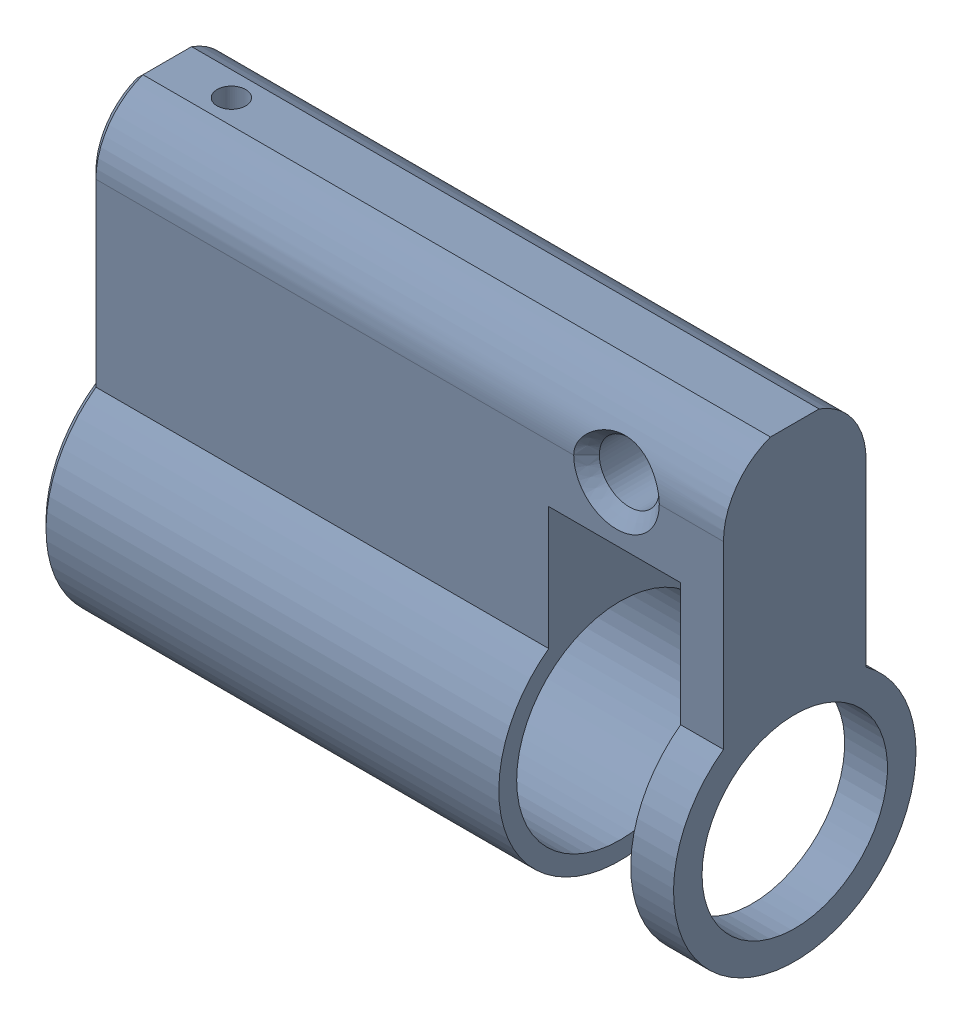
SolidWorks assembly cylinder_sub-assembly_e, configuration Default. Lengths in mm.
Overall size (44.5 32.7 17).
2 component instances, 2 part files, 0 mates.
Components (placement in the parent):
- cylinder_d_one-pair_of_pins-1: cylinder_d_one-pair_of_pins [Default] at origin size (44.5 32.7 17)
- upper_half_pin_y_cut_depth_2-1: upper_half_pin_y_cut_depth_2 [Default] at (5 15.25 0) x (1 0 0) z (0 -1 0) size (2 2 8)
